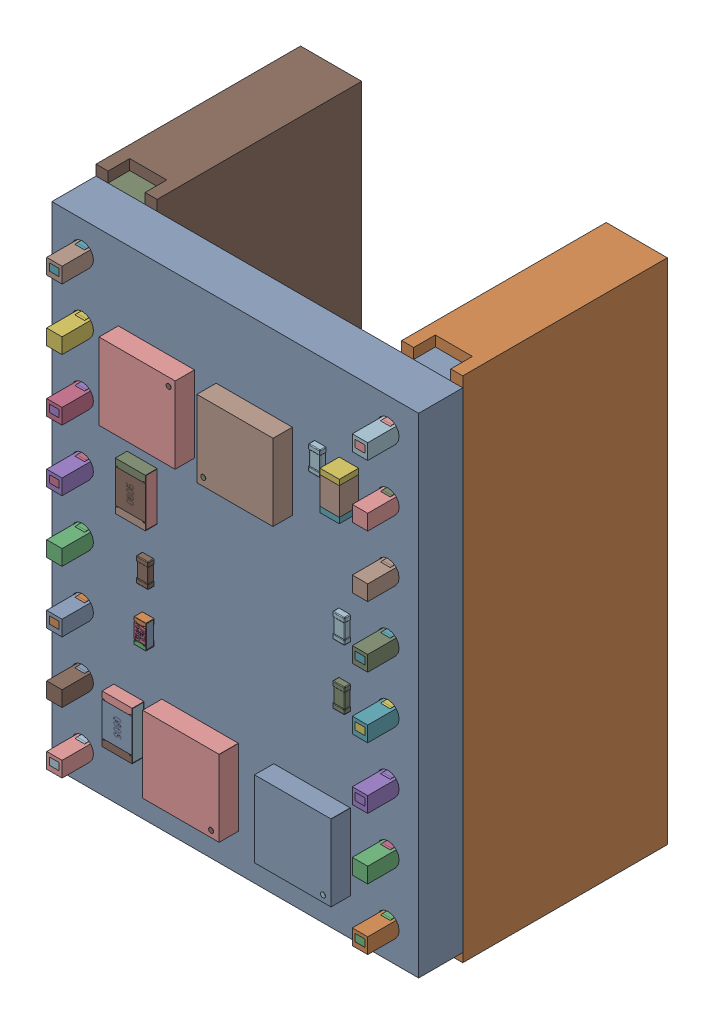
SolidWorks assembly MOTOR_DRIVER, configuration ﾃﾞﾌｫﾙﾄ. Lengths in mm.
Overall size (15.24 21.12 11.54).
82 component instances, 15 part files, 0 mates.
Components (placement in the parent):
- PCB-2-1: PCB-2 [ﾃﾞﾌｫﾙﾄ] at (-7.62 10.26 8.5) x (1 0 0) z (0 0 -1) size (15.24 21.12 11.54)
  - Board-2-1: Board-2 [ﾃﾞﾌｫﾙﾄ] at origin size (15.24 20.32 1.83)
    - Open CASCADE STEP translator 6.8 2.1.1-1: Open CASCADE STEP translator 6.8 2.1.1 [ﾃﾞﾌｫﾙﾄ] at (0 0 -1.8339) size (15.24 20.32 1.83)
  - X-1: X [ﾃﾞﾌｫﾙﾄ] at origin size (15.24 21.12 11.5)
    - DS1023-1x8SF11-1: DS1023-1x8SF11 [ﾃﾞﾌｫﾙﾄ] at (13.9593 19.0061 0) x (0 -1 0) z (0 0 1) size (21.12 2.54 11.5)
    - DS1023-1x8SF11-2: DS1023-1x8SF11 [ﾃﾞﾌｫﾙﾄ] at (1.2593 19.0061 0) x (0 -1 0) z (0 0 1) size (21.12 2.54 11.5)
  - U5-1: U5 [ﾃﾞﾌｫﾙﾄ] at origin size (3.17 3.19 0.82)
    - 6641442208-1: 6641442208 [ﾃﾞﾌｫﾙﾄ] at (8.4975 4.6 -2.7339) size (3.17 3.19 0.81)
      - Extruded-19-1: Extruded-19 [ﾃﾞﾌｫﾙﾄ] at origin size (3.17 3.19 0.81)
    - 6641441808-1: 6641441808 [ﾃﾞﾌｫﾙﾄ] at (7.1852 5.8608 -2.7339) x (0 -1 0) z (0 0 -1) size (0.2 0.2 0.01)
      - Cylinder-20-1: Cylinder-20 [ﾃﾞﾌｫﾙﾄ] at origin size (0.2 0.2 0.01)
  - U1-1: U1 [ﾃﾞﾌｫﾙﾄ] at origin size (3.19 3.17 0.82)
    - 6641441568-1: 6641441568 [ﾃﾞﾌｫﾙﾄ] at (6.25 17.0875 -2.7339) size (3.19 3.17 0.81)
      - Extruded-21-1: Extruded-21 [ﾃﾞﾌｫﾙﾄ] at origin size (3.19 3.17 0.81)
    - 6641441328-1: 6641441328 [ﾃﾞﾌｫﾙﾄ] at (7.5108 18.3998 -2.7339) x (-1 0 0) z (0 0 -1) size (0.2 0.2 0.01)
      - Cylinder-22-1: Cylinder-22 [ﾃﾞﾌｫﾙﾄ] at origin size (0.2 0.2 0.01)
  - C8-1: C8 [ﾃﾞﾌｫﾙﾄ] at origin size (0.5 1 0.5)
    - User_Library-C0402-1-1: User_Library-C0402-1 [ﾃﾞﾌｫﾙﾄ] at (11.385 3.6234 -1.8339) x (0 -1 0) z (0 0 -1) size (1 0.5 0.5)
  - R9-1: R9 [ﾃﾞﾌｫﾙﾄ] at origin size (0.5 1 0.35)
    - User_Library-User_Library-RES0402-2-1: User_Library-User_Library-RES0402-2 [ﾃﾞﾌｫﾙﾄ] at (3.9988 13.3623 -1.8339) x (0 1 0) z (0 0 -1) size (1 0.5 0.35)
  - R1-1: R1 [ﾃﾞﾌｫﾙﾄ] at origin size (0.5 1 0.35)
    - User_Library-User_Library-RES0402-2-1: User_Library-User_Library-RES0402-2 [ﾃﾞﾌｫﾙﾄ] at (3.1812 17.5123 0) x (0 1 0) z (0 0 1) size (1 0.5 0.35)
  - C3-1: C3 [ﾃﾞﾌｫﾙﾄ] at origin size (0.5 1 0.5)
    - User_Library-C0402-1-1: User_Library-C0402-1 [ﾃﾞﾌｫﾙﾄ] at (11.895 11.6466 -1.8339) x (0 1 0) z (0 0 -1) size (1 0.5 0.5)
  - U4-1: U4 [ﾃﾞﾌｫﾙﾄ] at origin size (3.17 3.19 0.82)
    - 6641442208-1: 6641442208 [ﾃﾞﾌｫﾙﾄ] at (4.4325 4.57 -2.7339) size (3.17 3.19 0.81)
      - Extruded-19-1: Extruded-19 [ﾃﾞﾌｫﾙﾄ] at origin size (3.17 3.19 0.81)
    - 6641440128-1: 6641440128 [ﾃﾞﾌｫﾙﾄ] at (5.7448 3.3092 -2.7339) x (0 1 0) z (0 0 -1) size (0.2 0.2 0.01)
      - Cylinder-23-1: Cylinder-23 [ﾃﾞﾌｫﾙﾄ] at origin size (0.2 0.2 0.01)
  - U3-1: U3 [ﾃﾞﾌｫﾙﾄ] at origin size (3.19 3.17 0.82)
    - 6641441328-1: 6641441328 [ﾃﾞﾌｫﾙﾄ] at (12.1608 18.3998 -2.7339) x (-1 0 0) z (0 0 -1) size (0.2 0.2 0.01)
      - Cylinder-22-1: Cylinder-22 [ﾃﾞﾌｫﾙﾄ] at origin size (0.2 0.2 0.01)
    - 6641441568-1: 6641441568 [ﾃﾞﾌｫﾙﾄ] at (10.9 17.0875 -2.7339) size (3.19 3.17 0.81)
      - Extruded-21-1: Extruded-21 [ﾃﾞﾌｫﾙﾄ] at origin size (3.19 3.17 0.81)
  - C1-1: C1 [ﾃﾞﾌｫﾙﾄ] at origin size (0.5 1 0.5)
    - User_Library-C0402-1-1: User_Library-C0402-1 [ﾃﾞﾌｫﾙﾄ] at (9.535 17.4466 0) x (0 1 0) z (0 0 1) size (1 0.5 0.5)
  - C2-1: C2 [ﾃﾞﾌｫﾙﾄ] at origin size (1 0.5 0.5)
    - User_Library-C0402-1-1: User_Library-C0402-1 [ﾃﾞﾌｫﾙﾄ] at (10.4533 16.155 0) x (-1 0 0) z (0 0 1) size (1 0.5 0.5)
  - C4-1: C4 [ﾃﾞﾌｫﾙﾄ] at origin size (1 0.5 0.5)
    - User_Library-C0402-1-1: User_Library-C0402-1 [ﾃﾞﾌｫﾙﾄ] at (7.7766 4.515 0) x (1 0 0) z (0 0 1) size (1 0.5 0.5)
  - C5-1: C5 [ﾃﾞﾌｫﾙﾄ] at origin size (1 0.5 0.5)
    - User_Library-C0402-1-1: User_Library-C0402-1 [ﾃﾞﾌｫﾙﾄ] at (11.2534 3.655 0) x (-1 0 0) z (0 0 1) size (1 0.5 0.5)
  - C7-1: C7 [ﾃﾞﾌｫﾙﾄ] at origin size (0.81 1.6 0.8)
    - 6641443168-1: 6641443168 [ﾃﾞﾌｫﾙﾄ] at (12.3314 3.3249 -2.6339) size (0.8 0.23 0.8)
      - Extruded-24-1: Extruded-24 [ﾃﾞﾌｫﾙﾄ] at origin size (0.8 0.23 0.8)
    - 6641443168-2: 6641443168 [ﾃﾞﾌｫﾙﾄ] at (12.3314 4.6949 -2.6339) size (0.8 0.23 0.8)
      - Extruded-24-1: Extruded-24 [ﾃﾞﾌｫﾙﾄ] at origin size (0.8 0.23 0.8)
    - 6641442768-1: 6641442768 [ﾃﾞﾌｫﾙﾄ] at (12.3313 4.0099 -2.6339) size (0.8 1.14 0.8)
      - Extruded-25-1: Extruded-25 [ﾃﾞﾌｫﾙﾄ] at origin size (0.8 1.14 0.8)
  - C11-1: C11 [ﾃﾞﾌｫﾙﾄ] at origin size (1 0.5 0.5)
    - User_Library-C0402-1-1: User_Library-C0402-1 [ﾃﾞﾌｫﾙﾄ] at (6.8766 18.415 0) x (1 0 0) z (0 0 1) size (1 0.5 0.5)
  - C12-1: C12 [ﾃﾞﾌｫﾙﾄ] at origin size (0.5 1 0.5)
    - User_Library-C0402-1-1: User_Library-C0402-1 [ﾃﾞﾌｫﾙﾄ] at (3.095 3.6734 0) x (0 -1 0) z (0 0 1) size (1 0.5 0.5)
  - C13-1: C13 [ﾃﾞﾌｫﾙﾄ] at origin size (0.5 1 0.5)
    - User_Library-C0402-1-1: User_Library-C0402-1 [ﾃﾞﾌｫﾙﾄ] at (4.235 11.2234 -1.8339) x (0 -1 0) z (0 0 -1) size (1 0.5 0.5)
  - C14-1: C14 [ﾃﾞﾌｫﾙﾄ] at origin size (0.5 1 0.5)
    - User_Library-C0402-1-1: User_Library-C0402-1 [ﾃﾞﾌｫﾙﾄ] at (11.895 9.1466 -1.8339) x (0 1 0) z (0 0 -1) size (1 0.5 0.5)
  - C15-1: C15 [ﾃﾞﾌｫﾙﾄ] at origin size (0.5 1 0.5)
    - User_Library-C0402-1-1: User_Library-C0402-1 [ﾃﾞﾌｫﾙﾄ] at (12.485 4.8966 0) x (0 1 0) z (0 0 1) size (1 0.5 0.5)
  - J3-1: J3 [ﾃﾞﾌｫﾙﾄ] at origin size (2.54 20.32 11.54)
    - 1001-8-1: 1001-8 [ﾃﾞﾌｫﾙﾄ] at (1.259 19.037 0) x (0 -1 0) z (0 0 1) size (20.32 2.54 11.54)
  - J4-1: J4 [ﾃﾞﾌｫﾙﾄ] at origin size (2.54 20.32 11.54)
    - 1001-8-1: 1001-8 [ﾃﾞﾌｫﾙﾄ] at (13.959 19.037 0) x (0 -1 0) z (0 0 1) size (20.32 2.54 11.54)
  - R2-1: R2 [ﾃﾞﾌｫﾙﾄ] at origin size (1.25 2 0.5)
    - User_Library-R_0805-1: User_Library-R_0805 [ﾃﾞﾌｫﾙﾄ] at (3.19 17.0633 -1.8239) x (0 1 0) z (0 0 -1) size (2 1.25 0.5)
  - R3-1: R3 [ﾃﾞﾌｫﾙﾄ] at origin size (0.5 1 0.35)
    - User_Library-User_Library-RES0402-2-1: User_Library-User_Library-RES0402-2 [ﾃﾞﾌｫﾙﾄ] at (7.4488 17.1077 0) x (0 -1 0) z (0 0 1) size (1 0.5 0.35)
  - R4-1: R4 [ﾃﾞﾌｫﾙﾄ] at origin size (1 0.5 0.35)
    - User_Library-User_Library-RES0402-2-1: User_Library-User_Library-RES0402-2 [ﾃﾞﾌｫﾙﾄ] at (3.5377 15.3012 0) x (-1 0 0) z (0 0 1) size (1 0.5 0.35)
  - R6-1: R6 [ﾃﾞﾌｫﾙﾄ] at origin size (0.5 1 0.35)
    - User_Library-User_Library-RES0402-2-1: User_Library-User_Library-RES0402-2 [ﾃﾞﾌｫﾙﾄ] at (4.3312 17.5123 0) x (0 1 0) z (0 0 1) size (1 0.5 0.35)
  - R8-1: R8 [ﾃﾞﾌｫﾙﾄ] at origin size (0.5 1 0.35)
    - User_Library-User_Library-RES0402-2-1: User_Library-User_Library-RES0402-2 [ﾃﾞﾌｫﾙﾄ] at (6.2312 17.1123 0) x (0 1 0) z (0 0 1) size (1 0.5 0.35)
  - U2-1: U2 [ﾃﾞﾌｫﾙﾄ] at origin size (8 8 1)
    - 6641437328-1: 6641437328 [ﾃﾞﾌｫﾙﾄ] at (8.169 10.388 0) size (8 8 1)
      - Extruded-26-1: Extruded-26 [ﾃﾞﾌｫﾙﾄ] at origin size (8 8 1)
    - 6641437008-1: 6641437008 [ﾃﾞﾌｫﾙﾄ] at (11.439 13.736 0) x (0 -1 0) z (0 0 1) size (0.4 0.4 1)
      - Cylinder-27-1: Cylinder-27 [ﾃﾞﾌｫﾙﾄ] at origin size (0.4 0.4 1)
  - R7-1: R7 [ﾃﾞﾌｫﾙﾄ] at origin size (1.25 2 0.5)
    - User_Library-R_0805-1: User_Library-R_0805 [ﾃﾞﾌｫﾙﾄ] at (3.74 8.4067 -1.8239) x (0 -1 0) z (0 0 -1) size (2 1.25 0.5)
  - C10-1: C10 [ﾃﾞﾌｫﾙﾄ] at origin size (1 0.5 0.5)
    - User_Library-C0402-1-1: User_Library-C0402-1 [ﾃﾞﾌｫﾙﾄ] at (9.0534 19.305 0) x (-1 0 0) z (0 0 1) size (1 0.5 0.5)
